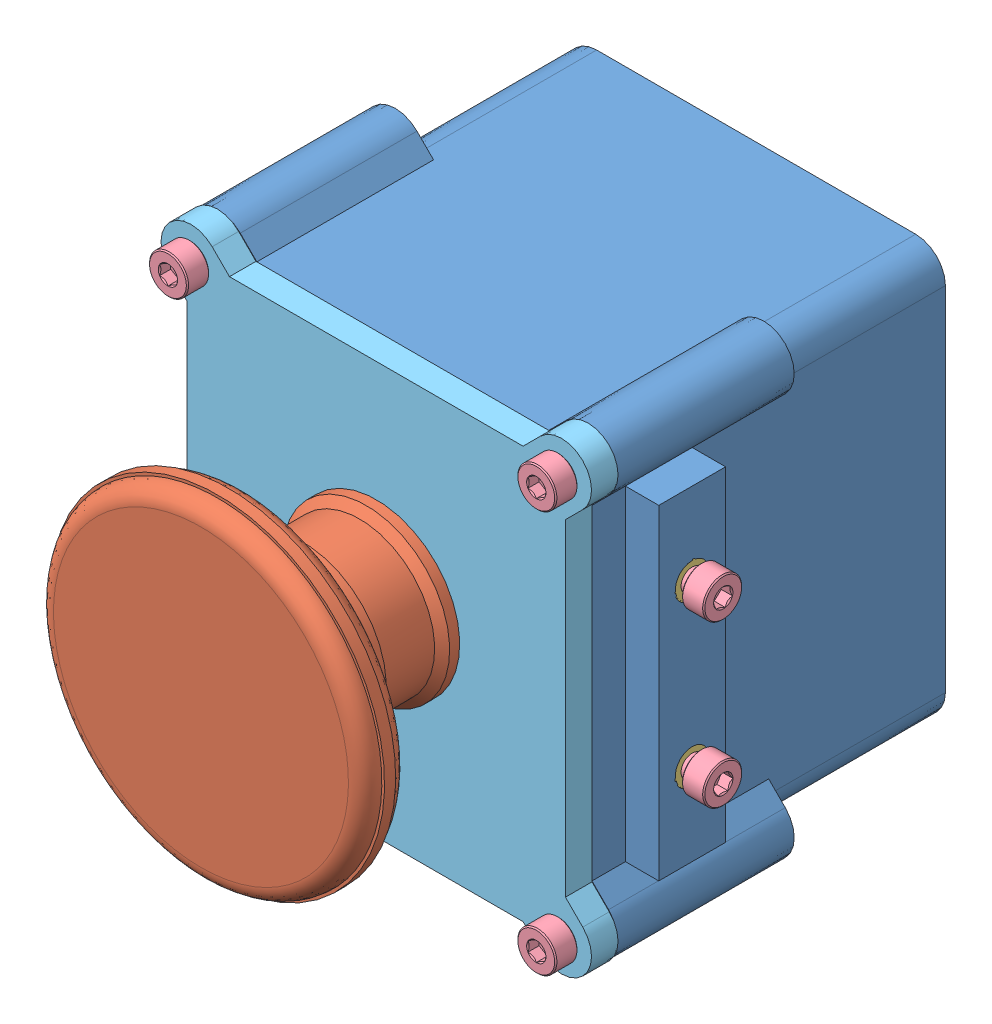
SolidWorks assembly EL-A0103-AA-E-Stop Assembly1, configuration Right E-Stop. Lengths in mm.
Overall size (91.52 87.91 99.76).
23 component instances, 6 part files, 29 mates.
Components (placement in the parent):
- EL-50052-AA-E-Stop Enclosure1-1: EL-50052-AA-E-Stop Enclosure1 [Default] at (9.3334 1.7352 -11.0704) size (80 83.18 63.5)
- EL-0002XX-AA-E-Stop1-1: EL-0002XX-AA-E-Stop1 [Default] at (9.3334 2.2352 24.9421) x (-1 0 0) z (0 0 1) size (60 60 87)
- FS-Heat Set Insert, M4x7-4.7 (94180A351)-1: FS-Heat Set Insert, M4x7-4.7 (94180A351) [94180A351] at (42.4247 37.8266 18.3296) size (6.35 6.35 4.7)
- BR-Black Oxide C12.9 SHCS, M4x0.7-8 (91290A140)1-1: BR-Black Oxide C12.9 SHCS, M4x0.7-8 (91290A140)1 [91290A140] at (42.4247 37.8266 23.783) size (7 7 12.17)
- BR-Black Oxide C12.9 SHCS, M4x0.7-8 (91290A140)1-2: BR-Black Oxide C12.9 SHCS, M4x0.7-8 (91290A140)1 [91290A140] at (-23.758 37.8266 23.783) size (7 7 12.17)
- FS-Heat Set Insert, M4x7-4.7 (94180A351)-2: FS-Heat Set Insert, M4x7-4.7 (94180A351) [94180A351] at (-23.758 37.8266 18.3296) x (1 0 0) z (0 0 -1) size (6.35 6.35 4.7)
- BR-Black Oxide C12.9 SHCS, M4x0.7-8 (91290A140)1-3: BR-Black Oxide C12.9 SHCS, M4x0.7-8 (91290A140)1 [91290A140] at (42.4247 -34.3562 23.783) x (-1 0 0) z (0 0 1) size (7 7 12.17)
- FS-Heat Set Insert, M4x7-4.7 (94180A351)-3: FS-Heat Set Insert, M4x7-4.7 (94180A351) [94180A351] at (42.4247 -34.3562 18.3296) x (1 0 0) z (0 0 -1) size (6.35 6.35 4.7)
- BR-Black Oxide C12.9 SHCS, M4x0.7-8 (91290A140)1-4: BR-Black Oxide C12.9 SHCS, M4x0.7-8 (91290A140)1 [91290A140] at (-23.758 -34.3562 23.783) x (-1 0 0) z (0 0 1) size (7 7 12.17)
- FS-Heat Set Insert, M4x7-4.7 (94180A351)-4: FS-Heat Set Insert, M4x7-4.7 (94180A351) [94180A351] at (-23.758 -34.3562 18.3296) size (6.35 6.35 4.7)
- EL-50051-AA-E-Stop Lid1-1: EL-50051-AA-E-Stop Lid1 [Default] at (9.3313 1.7401 20.6796) size (77.36 83.36 4.76)
- EL-20050-AA-E-Stop Brackets1-7: EL-20050-AA-E-Stop Brackets1 [Default] at (50.9209 1.4029 6.5197) x (0 0 1) z (-1 0 0) (suppressed, hidden)
- FS-Heat Set Insert, M4x7-4.7 (94180A351)-5: FS-Heat Set Insert, M4x7-4.7 (94180A351) [94180A351] at (46.9834 -12.604 8.6796) x (0 0 -1) z (1 0 0) size (6.35 6.35 4.7)
- FS-Heat Set Insert, M4x7-4.7 (94180A351)-10: FS-Heat Set Insert, M4x7-4.7 (94180A351) [94180A351] at (46.9834 16.352 8.6796) x (0 1 0) z (1 0 0) size (6.35 6.35 4.7)
- FS-Heat Set Insert, M4x7-4.7 (94180A351)-11: FS-Heat Set Insert, M4x7-4.7 (94180A351) [94180A351] at (-29.9041 16.352 8.6796) x (0 -1 0) z (-1 0 0) size (6.35 6.35 4.7)
- FS-Heat Set Insert, M4x7-4.7 (94180A351)-12: FS-Heat Set Insert, M4x7-4.7 (94180A351) [94180A351] at (-28.3591 -12.604 8.6796) x (0 1 0) z (-1 0 0) size (6.35 6.35 4.7)
- EL-20050-AA-E-Stop Brackets1-8: EL-20050-AA-E-Stop Brackets1 [Default] at (49.3334 2.3531 6.5197) x (0 0 1) z (1 0 0)
- BR-Black Oxide C12.9 SHCS, M4x0.7-8 (91290A140)1-9: BR-Black Oxide C12.9 SHCS, M4x0.7-8 (91290A140)1 [91290A140] at (48.9209 -12.604 8.6796) x (0 1 0) z (1 0 0) size (7 7 12.17)
- BR-Black Oxide C12.9 SHCS, M4x0.7-8 (91290A140)1-10: BR-Black Oxide C12.9 SHCS, M4x0.7-8 (91290A140)1 [91290A140] at (48.9209 16.36 8.6796) x (0 0.215824 -0.976432) z (1 0 0) size (7 7 12.17)
- EL-20050-AA-E-Stop Brackets1-9: EL-20050-AA-E-Stop Brackets1 [Default] at (-30.6666 2.3531 10.8396) x (0 0 -1) z (-1 0 0)
- BR-Black Oxide C12.9 SHCS, M4x0.7-8 (91290A140)1-11: BR-Black Oxide C12.9 SHCS, M4x0.7-8 (91290A140)1 [91290A140] at (-30.2541 16.352 8.6796) x (0 -0.196025 0.980599) z (-1 0 0) size (7 7 12.17)
- BR-Black Oxide C12.9 SHCS, M4x0.7-8 (91290A140)1-12: BR-Black Oxide C12.9 SHCS, M4x0.7-8 (91290A140)1 [91290A140] at (-30.2541 -12.604 8.6796) x (0 0.973175 -0.230068) z (-1 0 0) size (7 7 12.17)
- EL-20050-AA-E-Stop Brackets1-10: EL-20050-AA-E-Stop Brackets1 [Default] at (-30.6666 1.4029 6.5197) x (0 0 1) z (-1 0 0) (suppressed, hidden)
Mates (geometry in assembly coordinates):
- Width7: width anti-aligned: plane of EL-50052-AA-E-Stop Enclosure-1 through (37.3334 38.7352 20.6796) normal (-1 0 0); plane of EL-0002XX-AA-E-Stop-1 through (-18.6666 -35.2648 20.6796) normal (1 0 0); plane of EL-50052-AA-E-Stop Enclosure-1 through (31.8334 -11.2651 -24.2579) normal (1 0 0); plane of EL-0002XX-AA-E-Stop-1 through (-13.1666 -11.2651 -24.2579) normal (-1 0 0)
- Distance1: distance = 8 mm anti-aligned: plane of EL-0002XX-AA-E-Stop-1 through (-13.1666 24.7352 9.2421) normal (0 1 0); plane of EL-50052-AA-E-Stop Enclosure-1 through (43.3334 32.7352 20.6796) normal (0 -1 0)
- Concentric1: concentric aligned: cylinder of EL-50052-AA-E-Stop Enclosure-1 through (42.4247 37.8266 11.6796) axis (0 0 1) radius 3.025; cylinder of FS-Heat Set Insert, M4x7-4.7 (94180A351)-1 through (42.4247 37.8266 20.6796) axis (0 0 1) radius 2
- Coincident7: coincident aligned: plane of EL-50052-AA-E-Stop Enclosure-1 through (9.3334 1.7352 20.6796) normal (0 0 1); circle of FS-Heat Set Insert, M4x7-4.7 (94180A351)-1
- Concentric2: concentric anti-aligned: cylinder of FS-Heat Set Insert, M4x7-4.7 (94180A351)-1 through (42.4247 37.8266 20.6796) axis (0 0 1) radius 2; cylinder of BR-Black Oxide C12.9 SHCS, M4x0.7-8 (91290A140)-1 through (42.4247 37.8266 17.783) axis (0 0 -1) radius 2
- Coincident8: coincident anti-aligned: line of EL-50052-AA-E-Stop Enclosure-1 through (35.5552 38.7352 20.6796) axis (-1 0 0); line of EL-50051-AA-E-Stop Lid-1 through (-17.0466 38.7352 20.6796) axis (1 0 0)
- Coincident9: coincident anti-aligned: line of EL-50052-AA-E-Stop Enclosure-1 through (-24.6666 30.957 20.6796) axis (0 -1 0); line of EL-50051-AA-E-Stop Lid-1 through (-24.6666 -27.635 20.6796) axis (0 1 0)
- Coincident17: coincident anti-aligned: plane of EL-50052-AA-E-Stop Enclosure-1 through (49.3334 1.7352 -11.0704) normal (1 0 0); plane of EL-20050-AA-E-Stop Brackets-7 through (49.3334 1.4029 6.5197) normal (-1 0 0)
- Concentric20: concentric anti-aligned: cylinder of EL-50052-AA-E-Stop Enclosure-1 through (46.7934 -12.604 8.6796) axis (1 0 0) radius 3.025; cylinder of EL-20050-AA-E-Stop Brackets-7 through (49.3334 -12.604 8.6796) axis (-1 0 0) radius 2.25
- Concentric25: concentric anti-aligned: circle of EL-50052-AA-E-Stop Enclosure-1; circle of FS-Heat Set Insert, M4x7-4.7 (94180A351)-5
- Concentric34: concentric anti-aligned: circle of EL-50052-AA-E-Stop Enclosure-1; circle of FS-Heat Set Insert, M4x7-4.7 (94180A351)-10
- Concentric36: concentric aligned: circle of EL-50052-AA-E-Stop Enclosure-1; circle of FS-Heat Set Insert, M4x7-4.7 (94180A351)-12
- Concentric37: concentric aligned: circle of FS-Heat Set Insert, M4x7-4.7 (94180A351)-5; circle of EL-20050-AA-E-Stop Brackets-8
- Coincident26: coincident anti-aligned: plane of EL-50052-AA-E-Stop Enclosure-1 through (49.3334 1.7352 -11.0704) normal (1 0 0); plane of EL-20050-AA-E-Stop Brackets-8 through (49.3334 2.3531 6.5197) normal (-1 0 0)
- Parallel1: parallel anti-aligned: line of EL-50052-AA-E-Stop Enclosure-1 through (49.3334 30.957 14.6796) axis (0 0 -1); line of EL-20050-AA-E-Stop Brackets-8 through (49.3334 30.971 5.2188) axis (0 0 1)
- Concentric38: concentric anti-aligned: circle of EL-20050-AA-E-Stop Brackets-8; circle of BR-Black Oxide C12.9 SHCS, M4x0.7-8 (91290A140)-9
- Concentric39: concentric anti-aligned: circle of EL-20050-AA-E-Stop Brackets-8; circle of BR-Black Oxide C12.9 SHCS, M4x0.7-8 (91290A140)-10
- Concentric40: concentric aligned: circle of FS-Heat Set Insert, M4x7-4.7 (94180A351)-12; circle of EL-20050-AA-E-Stop Brackets-9
- Coincident28: coincident anti-aligned: plane of EL-50052-AA-E-Stop Enclosure-1 through (-30.6666 1.7352 -11.0704) normal (-1 0 0); plane of EL-20050-AA-E-Stop Brackets-9 through (-30.6666 2.3531 10.8396) normal (1 0 0)
- Parallel2: parallel aligned: line of EL-50052-AA-E-Stop Enclosure-1 through (-30.6666 30.957 14.6796) axis (0 0 -1); line of EL-20050-AA-E-Stop Brackets-9 through (-30.6666 30.971 12.1405) axis (0 0 -1)
- Coincident30: coincident anti-aligned: circle of FS-Heat Set Insert, M4x7-4.7 (94180A351)-11; circle of BR-Black Oxide C12.9 SHCS, M4x0.7-8 (91290A140)-11
- Concentric41: concentric anti-aligned: circle of EL-20050-AA-E-Stop Brackets-9; circle of BR-Black Oxide C12.9 SHCS, M4x0.7-8 (91290A140)-12
- Coincident31: coincident anti-aligned: plane of EL-20050-AA-E-Stop Brackets-8 through (50.9209 2.3531 6.5197) normal (1 0 0); plane of BR-Black Oxide C12.9 SHCS, M4x0.7-8 (91290A140)-9 through (50.9209 -12.604 11.9796) normal (-1 0 0)
- Coincident32: coincident anti-aligned: plane of EL-20050-AA-E-Stop Brackets-8 through (50.9209 2.3531 6.5197) normal (1 0 0); plane of BR-Black Oxide C12.9 SHCS, M4x0.7-8 (91290A140)-10 through (50.9209 19.5822 9.3919) normal (-1 0 0)
- Coincident34: coincident anti-aligned: plane of EL-20050-AA-E-Stop Brackets-9 through (-32.2541 2.3531 10.8396) normal (-1 0 0); plane of BR-Black Oxide C12.9 SHCS, M4x0.7-8 (91290A140)-12 through (-32.2541 -13.3632 5.4682) normal (1 0 0)
- Concentric42: concentric anti-aligned: circle of EL-50052-AA-E-Stop Enclosure-1; circle of BR-Black Oxide C12.9 SHCS, M4x0.7-8 (91290A140)-11
- Coincident36: coincident anti-aligned: plane of EL-20050-AA-E-Stop Brackets-9 through (-32.2541 2.3531 10.8396) normal (-1 0 0); circle of BR-Black Oxide C12.9 SHCS, M4x0.7-8 (91290A140)-11
- Parallel4: parallel aligned: plane of EL-50052-AA-E-Stop Enclosure-1 through (49.3334 1.7352 14.6796) normal (0 0 1); plane of EL-20050-AA-E-Stop Brackets-7 through (49.3334 1.4029 13.9189) normal (0 0 1)
- Coincident37: coincident anti-aligned: plane of EL-0002XX-AA-E-Stop-1 through (9.3334 2.2352 25.4421) normal (0 0 -1); plane of EL-50051-AA-E-Stop Lid-1 through (9.3313 1.7401 25.4421) normal (0 0 1)
